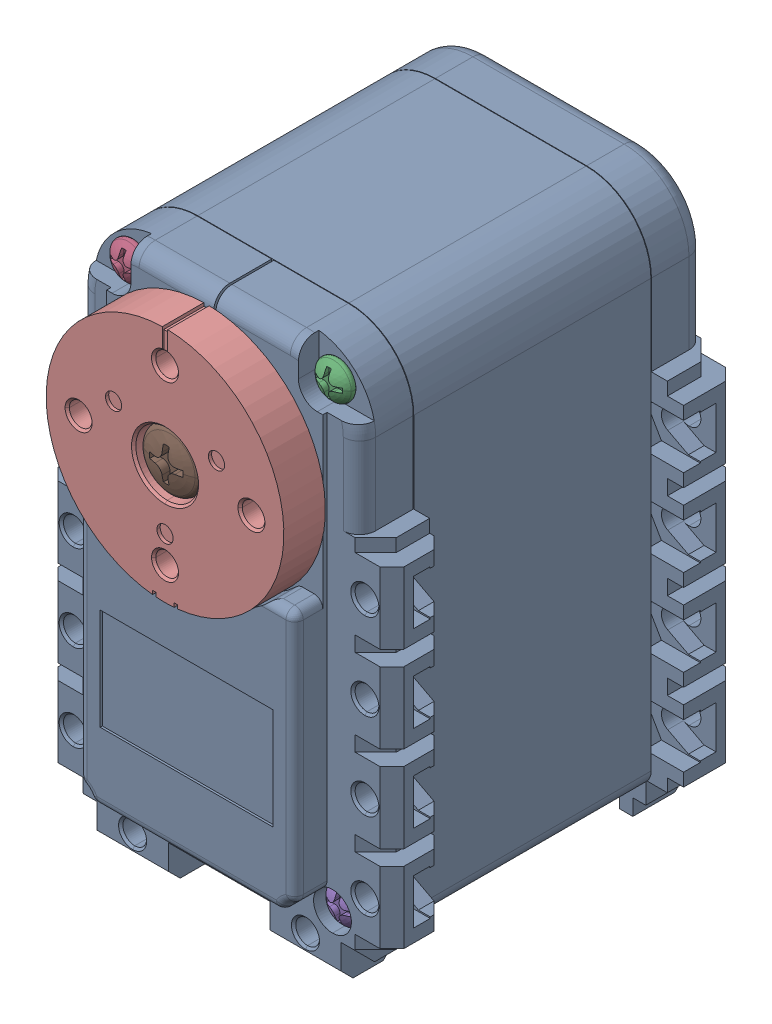
SolidWorks assembly AX-12A (1), configuration Default. Lengths in mm.
Overall size (32 50.01 40.05).
12 component instances, 7 part files, 0 mates.
Components (placement in the parent):
- ASM0002_ASM-1: ASM0002_ASM [Default] at origin size (32 50.01 40.05)
  - PRT0001-1: PRT0001 [Default] at origin size (32 50.01 38)
  - PRT0002-1: PRT0002 [Default] at (0 0 -2) x (-1 0 0) z (0 0 1) size (6.5 6.5 5.5)
  - PRT0003-1: PRT0003 [Default] at (9.5 8.5 14.5) x (-1 0 0) z (0 1 0) size (3.5 30.65 3.5)
  - PRT0003-2: PRT0003 [Default] at (-9.5 8.5 14.5) x (-1 0 0) z (0 1 0) size (3.5 30.65 3.5)
  - PRT0003-3: PRT0003 [Default] at (10.5 -33 14.5) x (-1 0 0) z (0 1 0) size (3.5 30.65 3.5)
  - PRT0003-4: PRT0003 [Default] at (-10.5 -33 14.5) x (-1 0 0) z (0 1 0) size (3.5 30.65 3.5)
  - PRT0004-1: PRT0004 [Default] at (5.05 -15.19 -9.75) x (1 0 0) z (0 1 0) size (9.9 9.4 4.9)
  - PRT0004-2: PRT0004 [Default] at (-4.95 -15.19 -9.75) x (1 0 0) z (0 1 0) size (9.9 9.4 4.9)
  - PRT0005-1: PRT0005 [Default] at (0 0 -18.4) x (-1 0 0) z (0 1 0) size (4.98 7 4.98)
  - PRT0006-1: PRT0006 [Default] at (0 0 19.16) x (0 1 0) z (0 0 1) size (22 22 6.7)
  - PRT0007-1: PRT0007 [Default] at (0 0 19.48) x (-1 0 0) z (0 1 0) size (5.5 9.57 5.5)
